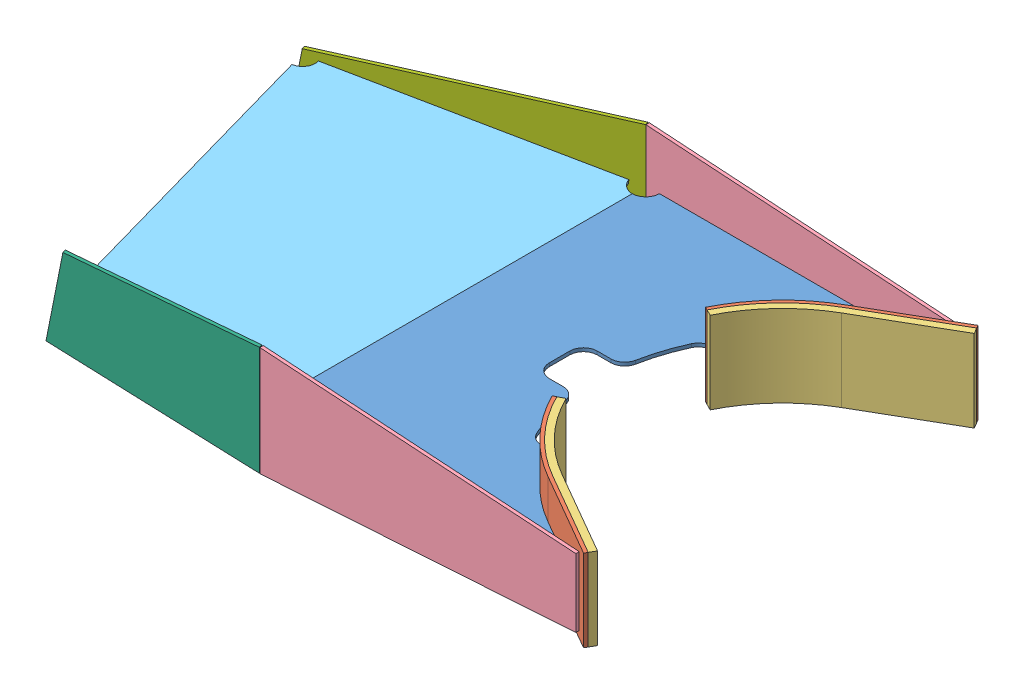
SolidWorks assembly 000013_REVB_FACE BOOM REST, configuration Default. Lengths in mm.
Overall size (1446.61 255.32 817.66).
9 component instances, 7 part files, 21 mates.
Components (placement in the parent):
- 000013-04_REVA_TOP WEB PLATE-1: 000013-04_REVA_TOP WEB PLATE [Default] at origin size (544.85 6.35 711.2)
- 000013-03_REVA_REST PLATE-1: 000013-03_REVA_REST PLATE [Default] x (0 1 0) z (0 0 1) size (152.4 285.48 226.92)
- 000022-XX_REVA_REST PAD-1: 000022-XX_REVA_REST PAD [Default] x (0 -1 0) z (0 0 -1) size (152.4 286.15 722.24)
- 000013-05_REVA_FLANGE PLATE 1-2: 000013-05_REVA_FLANGE PLATE 1 [Default] at (-609.6 0 -355.6) x (0 -1 0) z (0 0 1) size (203.2 587.38 6.35)
- 000013-06_REVA_BOTTOM WEB PLATE-2: 000013-06_REVA_BOTTOM WEB PLATE [Default] at (-609.6 0 0) x (0.997564 -0.069756 0) z (0 0 1) size (491.31 6.35 788.19)
- 000013-08_REVA_FLANGE PLATE 3-2: 000013-08_REVA_FLANGE PLATE 3 [Default] at (-609.6 0 355.6) x (0 1 0) z (-0.960927 0 0.2768) size (254.68 6.35 320.77)
- 000013-07_REVA_FLANGE PLATE 2-1: 000013-07_REVA_FLANGE PLATE 2 [Default] at (-609.6 0 -355.6) x (0 -1 0) z (-0.960978 0 0.276624) size (203.2 6.35 537.13)
- 000013-03_REVA_REST PLATE-3: 000013-03_REVA_REST PLATE [Default] x (0 -1 0) z (0 0 -1) size (152.4 285.48 226.92)
- 000013-05_REVA_FLANGE PLATE 1-4: 000013-05_REVA_FLANGE PLATE 1 [Default] at (-609.6 0 355.6) x (0 1 0) z (0 0 -1) size (203.2 587.38 6.35)
Mates (geometry in assembly coordinates):
- Coincident274: coincident anti-aligned: plane of 000013-04_REVA_TOP WEB PLATE-1 through (0 0 -355.6) normal (0 0 -1); plane of 000013-05_REVA_FLANGE PLATE 1-2 through (-609.6 0 -355.6) normal (0 0 1)
- Coincident275: coincident anti-aligned: plane of 000013-04_REVA_TOP WEB PLATE-1 through (0 0 0) normal (0 1 0); plane of 000013-05_REVA_FLANGE PLATE 1-2
- Coincident276: coincident anti-aligned: plane of 000013-04_REVA_TOP WEB PLATE-1 through (-609.6 0 -355.6) normal (-1 0 0); plane of 000013-05_REVA_FLANGE PLATE 1-2
- Parallel61: parallel anti-aligned: plane of 000013-04_REVA_TOP WEB PLATE-1 through (0 0 0) normal (0 0 1); plane of 000022-XX_REVA_REST PAD-1 through (0 0 0) normal (0 0 -1)
- Coincident277: coincident aligned: plane of 000013-03_REVA_REST PLATE-1 through (0 0 0) normal (0 0 1); plane of 000013-04_REVA_TOP WEB PLATE-1 through (0 0 0) normal (0 0 1)
- Coincident278: coincident aligned: plane of 000013-03_REVA_REST PLATE-1; plane of 000013-04_REVA_TOP WEB PLATE-1 through (0 0 0) normal (0 1 0)
- Concentric28: concentric aligned: cylinder of 000013-03_REVA_REST PLATE-1 through (0 76.2 0) axis (0 -1 0) radius 319.0875; cylinder of 000013-04_REVA_TOP WEB PLATE-1 through (0 0 0) axis (0 -1 0) radius 319.0875
- Concentric29: concentric anti-aligned: cylinder of 000013-03_REVA_REST PLATE-1 through (0 76.2 0) axis (0 -1 0) radius 312.7375; cylinder of 000022-XX_REVA_REST PAD-1 through (0 -76.2 0) axis (0 1 0) radius 312.7375
- Coincident279: coincident anti-aligned: plane of 000013-03_REVA_REST PLATE-1; plane of 000022-XX_REVA_REST PAD-1
- Coincident281: coincident aligned: plane of 000013-04_REVA_TOP WEB PLATE-1 through (0 0 0) normal (0 0 1); plane of assembly through (0 0 0) normal (0 0 1)
- Coincident282: coincident aligned: plane of 000013-04_REVA_TOP WEB PLATE-1 through (0 0 0) normal (0 1 0); plane of assembly through (0 0 0) normal (0 1 0)
- Coincident283: coincident aligned: plane of 000013-04_REVA_TOP WEB PLATE-1 through (0 0 0) normal (1 0 0); plane of assembly through (0 0 0) normal (1 0 0)
- Coincident298: coincident: point of 000013-04_REVA_TOP WEB PLATE-1; point of 000013-08_REVA_FLANGE PLATE 3-2
- Coincident299: coincident aligned: line of 000013-08_REVA_FLANGE PLATE 3-2 through (-609.6 -101.6 355.6) axis (0 1 0); line of 000013-05_REVA_FLANGE PLATE 1-4 through (-609.6 -101.6 355.6) axis (0 1 0)
- Angle2: planar angle = 0.288154 rad aligned: line of 000013-08_REVA_FLANGE PLATE 3-2 through (-609.6 0 355.6) axis (-0.95877 0.06697 0.276179); line of 000013-04_REVA_TOP WEB PLATE-1 through (0 0 355.6) axis (-1 0 0)
- Coincident305: coincident anti-aligned: line of 000013-04_REVA_TOP WEB PLATE-1 through (-609.6 0 -355.6) axis (0 0 1); line of 000013-06_REVA_BOTTOM WEB PLATE-2 through (-609.6 0 329.7113) axis (0 0 -1)
- Coincident306: coincident aligned: plane of 000013-06_REVA_BOTTOM WEB PLATE-2 through (-609.6 0 0) normal (0 0 1); plane of assembly through (0 0 0) normal (0 0 1)
- Angle3: planar angle = 0.069813 rad aligned: plane of 000013-04_REVA_TOP WEB PLATE-1 through (0 -3.175 0) normal (0 -1 0); plane of 000013-06_REVA_BOTTOM WEB PLATE-2 through (-1106.5242 31.5656 -212.1321) normal (-0.069756 -0.997564 0)
- Coincident309: coincident aligned: line of 000013-05_REVA_FLANGE PLATE 1-2 through (-609.6 101.6 -355.6) axis (0 -1 0); line of 000013-07_REVA_FLANGE PLATE 2-1 through (-609.6 101.6 -355.6) axis (0 -1 0)
- Coincident310: coincident: point of 000013-04_REVA_TOP WEB PLATE-1; point of 000013-07_REVA_FLANGE PLATE 2-1
- Parallel63: parallel: line of 000013-06_REVA_BOTTOM WEB PLATE-2 through (-633.9539 1.703 -348.1008) axis (-0.958816 0.067047 0.276002); plane of 000013-07_REVA_FLANGE PLATE 2-1
